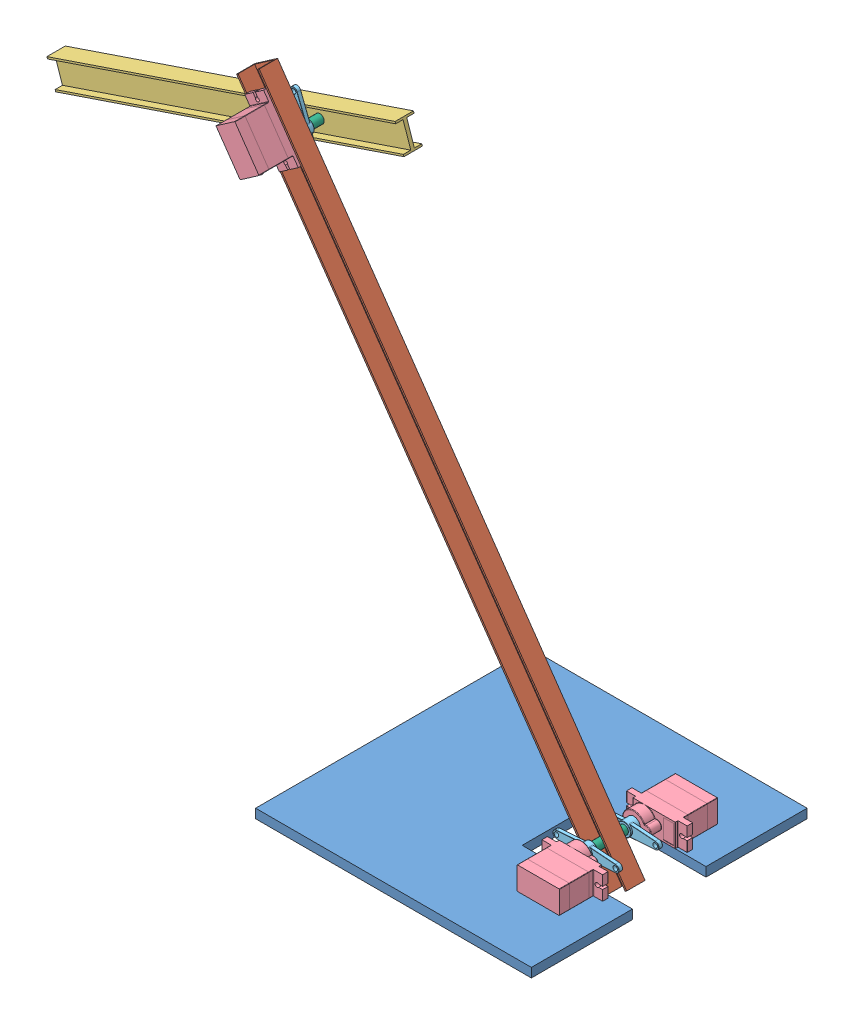
SolidWorks assembly Assem1, configuration Default. Lengths in mm.
Overall size (349.33 295.86 150).
11 component instances, 6 part files, 25 mates.
Components (placement in the parent):
- Base-1: Base [Default] at (-2.1939 74.4838 206.2446) size (150 5 150)
- Rod1-1: Rod1 [Default] at (232.9689 106.8385 112.7023) x (-0.57115 0.820846 0) z (0.820846 0.57115 0) size (350 10 15)
- Rod2-1: Rod2 [Default] at (-144.6636 318.1172 94.6906) x (0.947135 0.320836 0) z (0.320836 -0.947135 0) size (200 10 15)
- 舵机-1: 舵机 [默认] at (103.7405 85.7338 158.4873) x (1 0 0) z (0 1 0) size (33 32.3 12.5)
- servo arm-1: servo arm [默认] at (98.4905 85.7338 124.3873) x (1 0 0) z (0 -1 0) size (36 5.4 7.25)
- 舵机-2: 舵机 [默认] at (103.7405 85.7338 72.4873) x (1 0 0) z (0 -1 0) size (33 32.3 12.5)
- servo arm-2: servo arm [默认] at (98.4905 85.7338 106.5873) x (1 0 0) z (0 1 0) size (36 5.4 7.25)
- Part1-1: Part1 [Default] at (61.378 81.7088 105.5873) x (-0.908561 -0.417752 0) z (-0.417752 0.908561 0) size (4.8 19.8 4.8)
- 舵机-3: 舵机 [默认] at (-75.8529 336.297 142.5023) x (-0.57115 0.820846 0) z (-0.820846 -0.57115 0) size (33 32.3 12.5)
- servo arm-3: servo arm [默认] at (-72.8544 331.9876 107.3023) x (0.297282 -0.95479 0) z (-0.95479 -0.297282 0) size (36 5.4 7.25)
- Part1-2: Part1 [Default] at (-37.0248 342.4651 88.5023) x (0.821116 0.570761 0) z (0.570761 -0.821116 0) size (4.8 19.8 4.8)
Mates (geometry in assembly coordinates):
- Coincident1: coincident anti-aligned: plane of Base-1 through (-2.1939 79.4838 206.2446) normal (0 1 0); plane of 舵机-1 through (92.2405 79.4838 135.4873) normal (0 -1 0)
- Lock1: lock: unknown of Base-1; unknown of 舵机-1
- Coincident3: coincident anti-aligned: plane of Base-1 through (-2.1939 79.4838 206.2446) normal (0 1 0); plane of 舵机-2 through (92.2405 79.4838 95.4873) normal (0 -1 0)
- Coincident4: coincident anti-aligned: line of Base-1 through (131.9953 79.4838 95.4873) axis (-1 0 0); line of 舵机-2 through (100.0843 79.4838 95.4873) axis (1 0 0)
- Coincident5: coincident aligned: plane of 舵机-1 through (115.2405 79.4838 135.4873) normal (1 0 0); plane of 舵机-2 through (115.2405 91.9838 95.4873) normal (1 0 0)
- Coincident10: coincident anti-aligned: plane of 舵机-2 through (98.4905 85.7338 104.7873) normal (0 0 1); plane of servo arm-2 through (98.4905 85.7338 104.7873) normal (0 0 -1)
- Concentric1: concentric anti-aligned: circle of 舵机-2; circle of servo arm-2
- Coincident11: coincident anti-aligned: plane of 舵机-1 through (98.4905 85.7338 126.1873) normal (0 0 -1); plane of servo arm-1 through (98.4905 85.7338 126.1873) normal (0 0 1)
- Concentric2: concentric anti-aligned: circle of 舵机-1; circle of servo arm-1
- Concentric3: concentric anti-aligned: cylinder of Rod1-1 through (97.4434 85.7338 104.5908) axis (0 0 1) radius 2.5; cylinder of servo arm-1 through (97.4434 85.7338 129.7873) axis (0 0 -1) radius 3.625
- Lock2: lock: unknown of Rod1-1; unknown of Part1-1
- Coincident12: coincident anti-aligned: plane of servo arm-1 through (99.9405 85.7338 125.3873) normal (0 0 -1); plane of Part1-1 through (98.4905 85.7338 125.3873) normal (0 0 1)
- Coincident13: coincident anti-aligned: plane of servo arm-2 through (99.9405 85.7338 105.5873) normal (0 0 1); plane of Part1-1 through (98.4905 85.7338 105.5873) normal (0 0 -1)
- Concentric6: concentric anti-aligned: cylinder of servo arm-2 through (98.4905 85.7338 106.5873) axis (0 0 1) radius 2.4; cylinder of Part1-1 through (98.4905 85.7338 125.3873) axis (0 0 -1) radius 2.4
- Parallel2: parallel anti-aligned: line of Rod1-1 through (-84.6534 360.3254 113.7023) axis (0.57115 -0.820846 0); line of 舵机-3 through (-78.8949 329.7261 119.5023) axis (-0.57115 0.820846 0)
- Parallel3: parallel aligned: line of Rod1-1 through (-95.3244 352.9005 113.7023) axis (0.57115 -0.820846 0); line of 舵机-3 through (-77.1766 349.1423 119.5023) axis (0.57115 -0.820846 0)
- Coincident16: coincident anti-aligned: plane of Rod1-1 through (232.9689 106.8385 113.7023) normal (0 0 1); plane of 舵机-3 through (-72.8544 331.9876 113.7023) normal (0 0 -1)
- Concentric7: concentric aligned: circle of Rod1-1; circle of 舵机-3
- Concentric8: concentric anti-aligned: circle of 舵机-3; circle of servo arm-3
- Coincident21: coincident anti-aligned: plane of Rod1-1 through (232.9689 106.8385 112.7023) normal (0 0 -1); plane of servo arm-3 through (-72.8544 331.9876 112.7023) normal (0 0 1)
- Concentric9: concentric aligned: cylinder of Rod2-1 through (-72.8544 331.9876 108.6906) axis (0 0 -1) radius 2.4; cylinder of Part1-2 through (-72.8544 331.9876 108.3023) axis (0 0 -1) radius 2.4
- Parallel5: parallel aligned: cylinder of Rod2-1 through (-72.8544 331.9876 108.6906) axis (0 0 -1) radius 2.4; cylinder of Part1-2 through (-72.8544 331.9876 108.3023) axis (0 0 -1) radius 2.4
- Lock7: lock: unknown of servo arm-3; unknown of Part1-2
- Coincident23: coincident anti-aligned: circle of servo arm-3; circle of Part1-2
- Lock6: lock: unknown of Rod2-1; unknown of Part1-2
